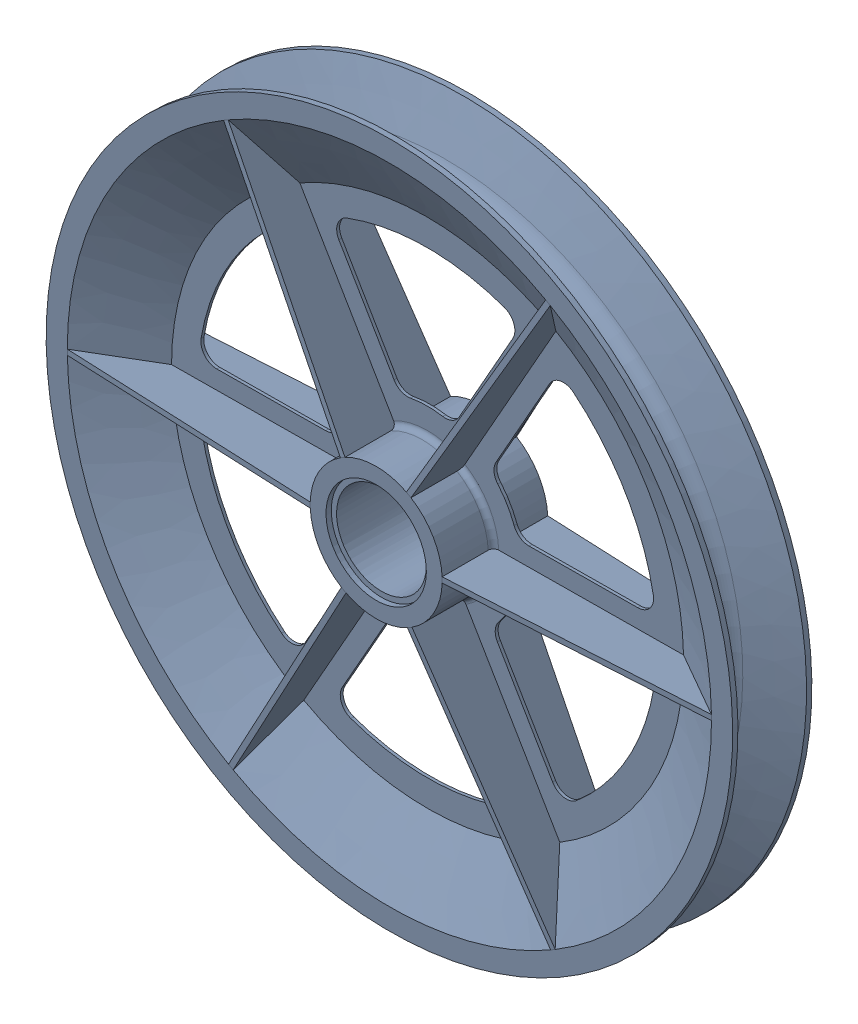
SolidWorks assembly Motor blus sheave, configuration Default. Lengths in mm.
Overall size (62.53 62.53 7.06).
7 component instances, 4 part files, 2 mates.
Components (placement in the parent):
- motor-1: motor [Default] at (5.5085 10.8533 -10.2803)
  - PM-33243000-100K Front.STEP-1: PM-33243000-100K Front.STEP [Default] at (0 -13.8472 0) (suppressed, hidden)
  - M1.6 Screw.STEP-1: M1.6 Screw.STEP [Default] at (-4.1152 1.511 17.9) x (0.707107 0.707107 0) z (0.707107 -0.707107 0) (suppressed, hidden)
  - M1.6 Screw.STEP-2: M1.6 Screw.STEP [Default] at (-11.243 -25.0902 17.9) x (-0.965926 0.258819 0) z (0.258819 0.965926 0) (suppressed, hidden)
  - M1.6 Screw.STEP-3: M1.6 Screw.STEP [Default] at (15.3582 -17.9624 17.9) x (0.258819 -0.965926 0) z (-0.965926 -0.258819 0) (suppressed, hidden)
  - PM-33243000-100K Back.STEP-1: PM-33243000-100K Back.STEP [Default] at (0 -13.8472 0.01) (suppressed, hidden)
- 11068-D-071-0 (CABLE SHEAVE 1020X170X31.8-1: 11068-D-071-0 (CABLE SHEAVE 1020X170X31.8 [Default] at (8.9733 0.4709 27.9346) x (0.870424 -0.492303 0) z (0 0 1) size (45.88 45.88 7.06)
Mates (geometry in assembly coordinates):
- Concentric1: concentric aligned: cylinder of motor-1/PM-33243000-100K Front.STEP-1 through (8.9733 0.4709 19.7197) axis (0 0 -1) radius 3; cylinder of 11068-D-071-0 (CABLE SHEAVE 1020X170X31.8-1 through (8.9733 0.4709 28.2873) axis (0 0 -1) radius 3
- Coincident1: coincident aligned: plane of motor-1/PM-33243000-100K Front.STEP-1 through (5.5085 -2.9939 31.7197) normal (0 0 1); plane of 11068-D-071-0 (CABLE SHEAVE 1020X170X31.8-1 through (8.9733 0.4709 31.7197) normal (0 0 1)
